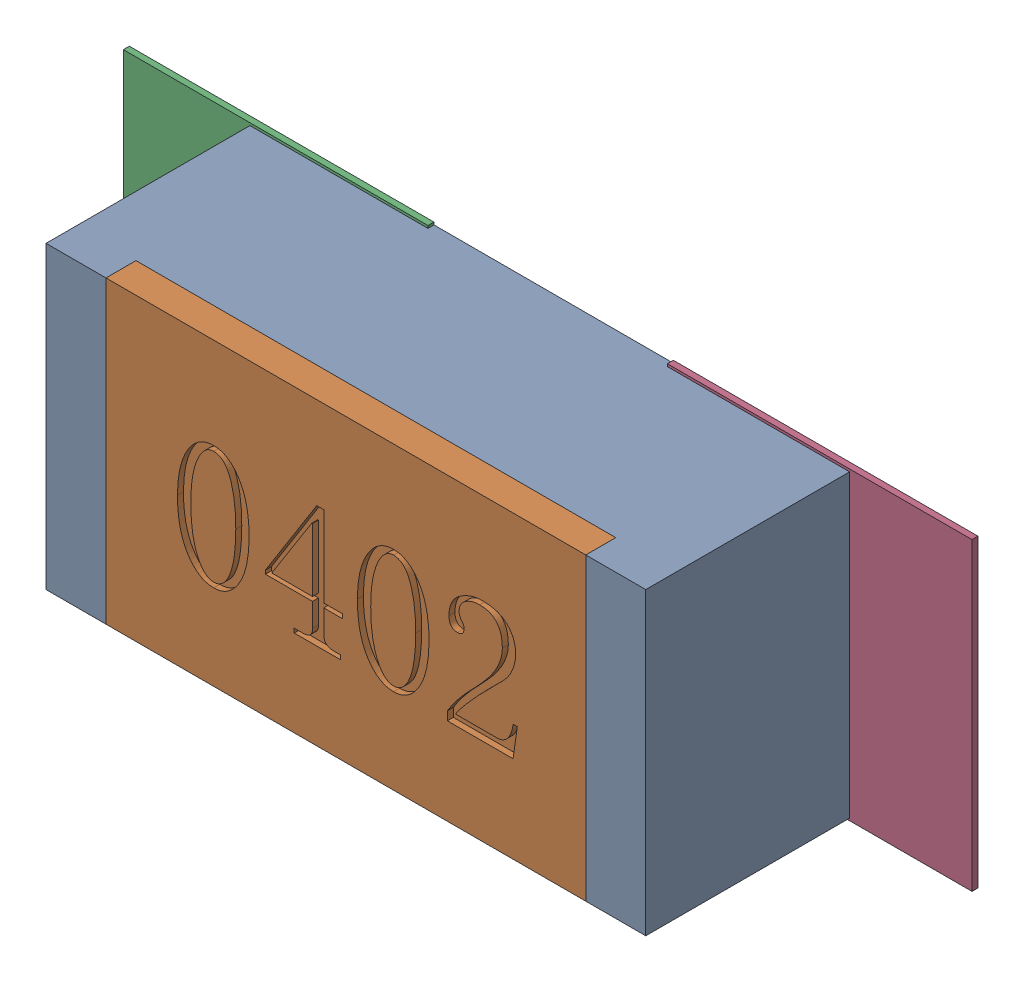
SolidWorks assembly R30, configuration Défaut. Lengths in mm.
Overall size (1.42 0.51 0.35).
5 component instances, 2 part files, 0 mates.
Components (placement in the parent):
- R0402-1: R0402 [Défaut] at (20.0914 -25.5525 0) x (1 0 0) z (0 0 1) size (1 0.5 0.35)
- 6504207776-1: 6504207776 [Défaut] at (19.6343 -25.5524 0) size (0.51 0.51 0.01)
  - Extruded-1: Extruded [Défaut] at origin size (0.51 0.51 0.01)
- 6504207776-2: 6504207776 [Défaut] at (20.5414 -25.5524 0) size (0.51 0.51 0.01)
  - Extruded-1: Extruded [Défaut] at origin size (0.51 0.51 0.01)
